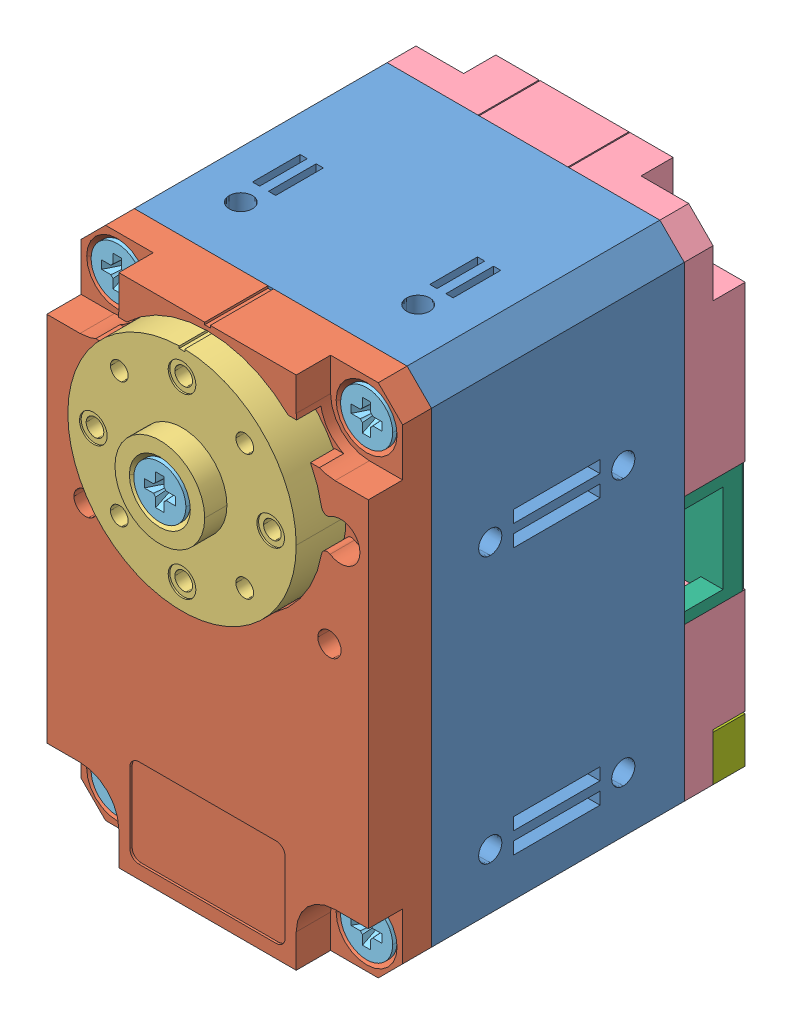
SolidWorks assembly XL430_W250_T, configuration Default. Lengths in mm.
Overall size (29 46.5 38.31).
16 component instances, 7 part files, 0 mates.
Components (placement in the parent):
- XL430_W250_T.STEP-1: XL430_W250_T.STEP [Default] at origin size (29 46.5 38.31)
  - Part1^XL430_W250_T.STEP-1: Part1^XL430_W250_T.STEP [Default] at origin size (29 46.5 22.8)
  - Part2^XL430_W250_T.STEP-1: Part2^XL430_W250_T.STEP [Default] at origin size (29 46.5 5.7)
  - Part3^XL430_W250_T.STEP-1: Part3^XL430_W250_T.STEP [Default] at (0 0 3.5) size (20.6 20.6 6.5)
  - Part4^XL430_W250_T.STEP-1: Part4^XL430_W250_T.STEP [Default] at (0 0 -22.8) x (-1 0 0) z (0 0 -1) size (29 46.5 5.5)
  - countersunk flat head cross recess screw_din_DIN EN ISO 7046-1 - M2.5 x 10 - Z - 10N.STEP-1: countersunk flat head cross recess screw_din_DIN EN ISO 7046-1 - M2.5 x 10 - Z - 10N.STEP [Default] at (11.25 -3.25 2.6) x (0 0 -1) z (1 0 0) size (10 4.7 4.7)
  - countersunk flat head cross recess screw_din_DIN EN ISO 7046-1 - M2.5 x 10 - Z - 10N.STEP-2: countersunk flat head cross recess screw_din_DIN EN ISO 7046-1 - M2.5 x 10 - Z - 10N.STEP [Default] at (-11.25 -3.25 2.6) x (0 0 -1) z (1 0 0) size (10 4.7 4.7)
  - countersunk flat head cross recess screw_din_DIN EN ISO 7046-1 - M2.5 x 10 - Z - 10N.STEP-3: countersunk flat head cross recess screw_din_DIN EN ISO 7046-1 - M2.5 x 10 - Z - 10N.STEP [Default] at (-11.25 -43.25 2.6) x (0 0 -1) z (1 0 0) size (10 4.7 4.7)
  - countersunk flat head cross recess screw_din_DIN EN ISO 7046-1 - M2.5 x 10 - Z - 10N.STEP-4: countersunk flat head cross recess screw_din_DIN EN ISO 7046-1 - M2.5 x 10 - Z - 10N.STEP [Default] at (11.25 -43.25 2.6) x (0 0 -1) z (1 0 0) size (10 4.7 4.7)
  - countersunk flat head cross recess screw_din_DIN EN ISO 7046-1 - M2.5 x 10 - Z - 10N.STEP-5: countersunk flat head cross recess screw_din_DIN EN ISO 7046-1 - M2.5 x 10 - Z - 10N.STEP [Default] at (0 -11 10) x (0 0 -1) z (1 0 0) size (10 4.7 4.7)
  - countersunk flat head cross recess screw_din_DIN EN ISO 7046-1 - M2.5 x 10 - Z - 10N.STEP-6: countersunk flat head cross recess screw_din_DIN EN ISO 7046-1 - M2.5 x 10 - Z - 10N.STEP [Default] at (11.25 -3.25 -25.4) x (0 0 1) z (-1 0 0) size (10 4.7 4.7)
  - countersunk flat head cross recess screw_din_DIN EN ISO 7046-1 - M2.5 x 10 - Z - 10N.STEP-7: countersunk flat head cross recess screw_din_DIN EN ISO 7046-1 - M2.5 x 10 - Z - 10N.STEP [Default] at (-11.25 -3.25 -25.4) x (0 0 1) z (-1 0 0) size (10 4.7 4.7)
  - countersunk flat head cross recess screw_din_DIN EN ISO 7046-1 - M2.5 x 10 - Z - 10N.STEP-8: countersunk flat head cross recess screw_din_DIN EN ISO 7046-1 - M2.5 x 10 - Z - 10N.STEP [Default] at (11.25 -43.25 -25.4) x (0 0 1) z (-1 0 0) size (10 4.7 4.7)
  - countersunk flat head cross recess screw_din_DIN EN ISO 7046-1 - M2.5 x 10 - Z - 10N.STEP-9: countersunk flat head cross recess screw_din_DIN EN ISO 7046-1 - M2.5 x 10 - Z - 10N.STEP [Default] at (-11.25 -43.25 -25.4) x (0 0 1) z (-1 0 0) size (10 4.7 4.7)
  - Part5^XL430_W250_T.STEP-1: Part5^XL430_W250_T.STEP [Default] at (0 0 -28.3) x (-1 0 0) z (0 0 -1) size (29 11.6 5.5)
  - Part6^XL430_W250_T.STEP-1: Part6^XL430_W250_T.STEP [Default] at (0 0 -25.4) x (-1 0 0) z (0 0 -1) size (6.3 6.3 2.9)
